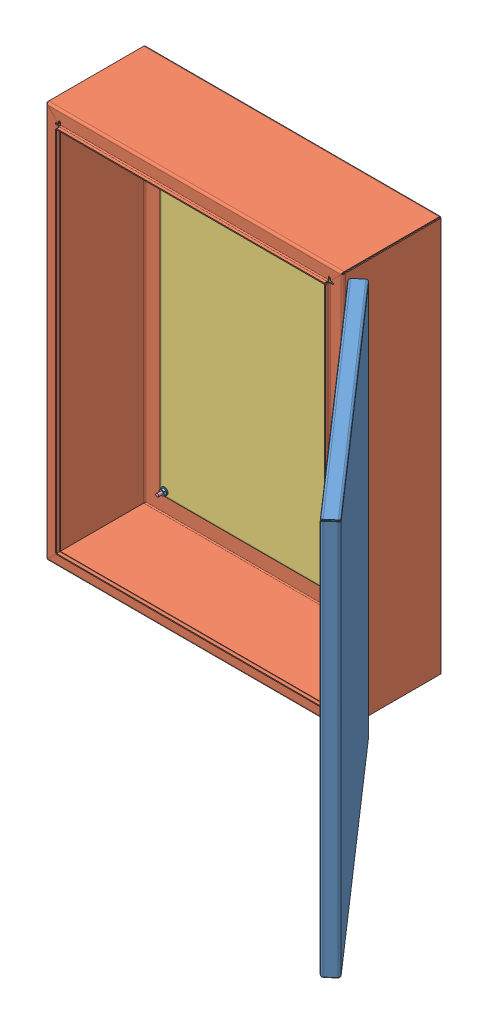
SolidWorks assembly HQ metal enclosure, configuration 600*800. Lengths in mm.
Overall size (1029.78 800 653.92).
17 component instances, 7 part files, 30 mates.
Components (placement in the parent):
- 01 enclosure door-1: 01 enclosure door [600*800] at (532.1831 0 406.4283) x (-0.658644 0 -0.752455) z (0.752455 0 -0.658644) size (600 800 30)
- 000 enclosure back-1: 000 enclosure back [600*800] at origin size (600 800 208)
- 02 enclosure inside rack-1: 02 enclosure inside rack [600*800] at (0 0 10) size (520 720 10)
- flat head screw_am-3: flat head screw_am [B18.6.7M - M6 x 1.0 x 25 Type I Cross Recessed FHMS --25N] at (-248 348 0) x (0 0 1) z (-1 0 0) size (25 11.3 11.3)
- flat head screw_am-8: flat head screw_am [B18.6.7M - M6 x 1.0 x 25 Type I Cross Recessed FHMS --25N] at (248 348 0) x (0 0 1) z (-0.987351 -0.158553 0) size (25 11.3 11.3)
- flat head screw_am-10: flat head screw_am [B18.6.7M - M6 x 1.0 x 25 Type I Cross Recessed FHMS --25N] at (248 -348 0) x (0 0 1) z (-0.959125 -0.282984 0) size (25 11.3 11.3)
- flat head screw_am-12: flat head screw_am [B18.6.7M - M6 x 1.0 x 25 Type I Cross Recessed FHMS --25N] at (-248 -348 0) x (0 0 1) z (-0.928571 -0.371154 0) size (25 11.3 11.3)
- hex flange nut_am-2: hex flange nut_am [B18.2.2.4M - Hex flange nut, M6 x 1 --N] at (-248 348 16) x (0.601969 -0.79852 0) z (0 0 1) size (14.2 14.2 6)
- hex flange nut_am-3: hex flange nut_am [B18.2.2.4M - Hex flange nut, M6 x 1 --N] at (248 348 16) x (0.369758 0.929128 0) z (0 0 1) size (14.2 14.2 6)
- hex flange nut_am-4: hex flange nut_am [B18.2.2.4M - Hex flange nut, M6 x 1 --N] at (-248 -348 16) x (-0.352717 -0.93573 0) z (0 0 1) size (14.2 14.2 6)
- hex flange nut_am-5: hex flange nut_am [B18.2.2.4M - Hex flange nut, M6 x 1 --N] at (248 -348 16) x (-0.244414 -0.969671 0) z (0 0 1) size (14.2 14.2 6)
- HQ metal enclosure HINGE-1: HQ metal enclosure HINGE [Default] at (300 282 228.0066) x (0 0 -1) z (1 0 0) size (60.83 70 17.71) (flexible)
  - enclosure HINGE2-1: enclosure HINGE2 [Default] at (45.6238 0 32.6581) x (-0.658644 0 -0.752455) z (0.752455 0 -0.658644) size (35.22 70 10.98)
  - enclosure HINGE1-1: enclosure HINGE1 [Default] at (60.4394 0 0) x (-1 0 0) z (0 0 1) size (35.22 70 10.98)
- HQ metal enclosure HINGE-2: HQ metal enclosure HINGE [Default] at (287.9147 -274.9874 221.4085) x (0 0 -1) z (1 0 0) size (60.83 70 17.71) (flexible)
  - enclosure HINGE2-1: enclosure HINGE2 [Default] at (39.0256 -7.0126 44.7434) x (-0.658644 0 -0.752455) z (0.752455 0 -0.658644) size (35.22 70 10.98)
  - enclosure HINGE1-1: enclosure HINGE1 [Default] at (53.8412 -7.0126 12.0853) x (-1 0 0) z (0 0 1) size (35.22 70 10.98)
Mates (geometry in assembly coordinates):
- Coincident2: coincident aligned: plane of enclosure door-1 through (532.1831 400 406.4283) normal (0 1 0); plane of enclosure back-1 through (0 400 0) normal (0 1 0)
- Coincident3: coincident anti-aligned: plane of enclosure back-1 through (0 0 0) normal (0 0 1); plane of enclosure inside rack-1 through (-260 360 0) normal (0 0 -1)
- Width1: width anti-aligned: plane of enclosure back-1 through (0 400 0) normal (0 1 0); plane of enclosure inside rack-1 through (0 -400 0) normal (0 -1 0); plane of enclosure back-1 through (0 -360 10) normal (0 -1 0); plane of enclosure inside rack-1 through (0 360 10) normal (0 1 0)
- Width3: width anti-aligned: plane of enclosure inside rack-1 through (-260 0 10) normal (-1 0 0); plane of enclosure back-1 through (260 0 10) normal (1 0 0); plane of enclosure inside rack-1 through (300 0 0) normal (1 0 0); plane of enclosure back-1 through (-300 0 0) normal (-1 0 0)
- Concentric1: concentric anti-aligned: cylinder of enclosure inside rack-1 through (-248 348 8) axis (0 0 1) radius 3.25; cylinder of flat head screw_am-3 through (-248 348 -6.35) axis (0 0 -1) radius 3
- Coincident4: coincident anti-aligned: plane of enclosure back-1 through (0 0 0) normal (0 0 1); plane of flat head screw_am-3 through (-248 348 0) normal (0 0 -1)
- Concentric6: concentric anti-aligned: cylinder of enclosure inside rack-1 through (248 348 8) axis (0 0 1) radius 3.25; cylinder of flat head screw_am-8 through (248 348 -6.35) axis (0 0 -1) radius 3
- Coincident7: coincident anti-aligned: plane of enclosure back-1 through (0 0 0) normal (0 0 1); plane of flat head screw_am-8 through (248 348 0) normal (0 0 -1)
- Concentric7: concentric anti-aligned: cylinder of enclosure inside rack-1 through (248 -348 8) axis (0 0 1) radius 3.25; cylinder of flat head screw_am-10 through (248 -348 -6.35) axis (0 0 -1) radius 3
- Coincident8: coincident anti-aligned: plane of enclosure back-1 through (0 0 0) normal (0 0 1); plane of flat head screw_am-10 through (248 -348 0) normal (0 0 -1)
- Concentric8: concentric anti-aligned: cylinder of enclosure inside rack-1 through (-248 -348 8) axis (0 0 1) radius 3.25; cylinder of flat head screw_am-12 through (-248 -348 -6.35) axis (0 0 -1) radius 3
- Coincident9: coincident anti-aligned: plane of enclosure back-1 through (0 0 0) normal (0 0 1); plane of flat head screw_am-12 through (-248 -348 0) normal (0 0 -1)
- Concentric9: concentric anti-aligned: cylinder of flat head screw_am-3 through (-248 348 -6.35) axis (0 0 -1) radius 3; cylinder of hex flange nut_am-2 through (-248 348 -9.0375) axis (0 0 1) radius 3
- Coincident10: coincident anti-aligned: plane of enclosure inside rack-1 through (0 0 10) normal (0 0 1); plane of hex flange nut_am-2 through (-243.3897 351.4755 10) normal (0 0 -1)
- Concentric10: concentric anti-aligned: cylinder of flat head screw_am-8 through (248 348 -6.35) axis (0 0 -1) radius 3; cylinder of hex flange nut_am-3 through (248 348 -9.0375) axis (0 0 1) radius 3
- Coincident11: coincident anti-aligned: plane of enclosure inside rack-1 through (0 0 10) normal (0 0 1); plane of hex flange nut_am-3 through (242.6357 350.1348 10) normal (0 0 -1)
- Concentric11: concentric anti-aligned: cylinder of flat head screw_am-12 through (-248 -348 -6.35) axis (0 0 -1) radius 3; cylinder of hex flange nut_am-4 through (-248 -348 -9.0375) axis (0 0 1) radius 3
- Coincident12: coincident anti-aligned: plane of enclosure inside rack-1 through (0 0 10) normal (0 0 1); plane of hex flange nut_am-4 through (-242.5976 -350.0364 10) normal (0 0 -1)
- Concentric12: concentric anti-aligned: cylinder of flat head screw_am-10 through (248 -348 -6.35) axis (0 0 -1) radius 3; cylinder of hex flange nut_am-5 through (248 -348 -9.0375) axis (0 0 1) radius 3
- Coincident13: coincident anti-aligned: plane of enclosure inside rack-1 through (0 0 10) normal (0 0 1); plane of hex flange nut_am-5 through (253.5984 -349.4111 10) normal (0 0 -1)
- Coincident14: coincident anti-aligned: plane of enclosure back-1 through (300 0 0) normal (1 0 0); plane of HQ metal enclosure HINGE-1/enclosure HINGE1-1 through (300 247 167.5673) normal (-1 0 0)
- Concentric13: concentric aligned: cylinder of enclosure back-1 through (290 300 180) axis (1 0 0) radius 3.25; cylinder of HQ metal enclosure HINGE-1/enclosure HINGE1-1 through (308 300 180) axis (1 0 0) radius 2.75
- Concentric14: concentric aligned: cylinder of enclosure back-1 through (290 264 180) axis (1 0 0) radius 3.25; cylinder of HQ metal enclosure HINGE-1/enclosure HINGE1-1 through (308 264 180) axis (1 0 0) radius 2.75
- Coincident15: coincident anti-aligned: plane of enclosure door-1 through (334.5899 0 180.6919) normal (-0.658644 0 -0.752455); plane of HQ metal enclosure HINGE-1/enclosure HINGE2-1 through (332.6581 317 182.3828) normal (0.658644 0 0.752455)
- Coincident16: coincident anti-aligned: plane of enclosure back-1 through (300 0 0) normal (1 0 0); plane of HQ metal enclosure HINGE-2/enclosure HINGE1-1 through (300 -317 167.5673) normal (-1 0 0)
- Concentric15: concentric aligned: cylinder of enclosure back-1 through (290 -264 180) axis (1 0 0) radius 3.25; cylinder of HQ metal enclosure HINGE-2/enclosure HINGE1-1 through (308 -264 180) axis (1 0 0) radius 2.75
- Concentric16: concentric aligned: cylinder of enclosure back-1 through (290 -300 180) axis (1 0 0) radius 3.25; cylinder of HQ metal enclosure HINGE-2/enclosure HINGE1-1 through (308 -300 180) axis (1 0 0) radius 2.75
- Coincident19: coincident anti-aligned: plane of enclosure door-1 through (334.5899 0 180.6919) normal (-0.658644 0 -0.752455); plane of HQ metal enclosure HINGE-2/enclosure HINGE2-1 through (332.6581 -247 182.3828) normal (0.658644 0 0.752455)
- Concentric18: concentric aligned: cylinder of enclosure door-1 through (329.8895 300 198.0961) axis (-0.658644 0 -0.752455) radius 3.25; cylinder of HQ metal enclosure HINGE-1/enclosure HINGE2-1 through (318.0339 300 184.5519) axis (-0.658644 0 -0.752455) radius 2.75
- Concentric19: concentric aligned: cylinder of enclosure door-1 through (329.8895 264 198.0961) axis (-0.658644 0 -0.752455) radius 3.25; cylinder of HQ metal enclosure HINGE-1/enclosure HINGE2-1 through (318.0339 264 184.5519) axis (-0.658644 0 -0.752455) radius 2.75
